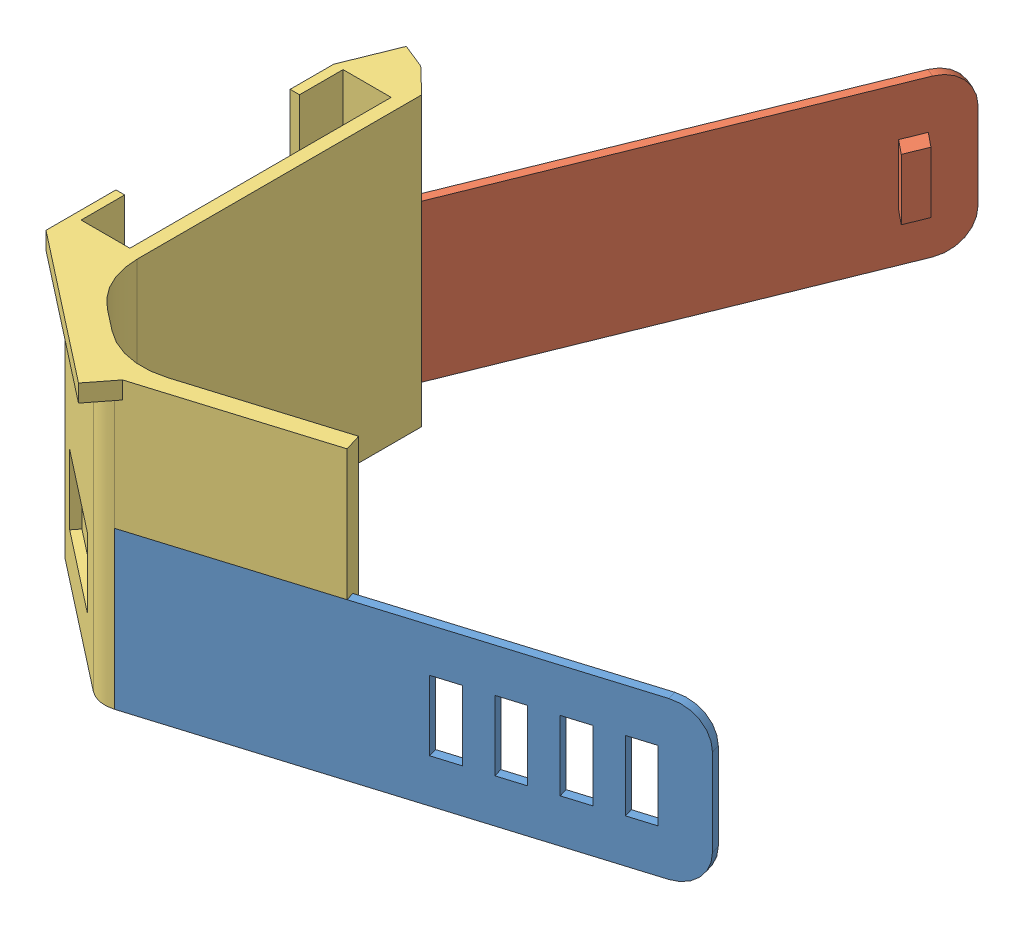
SolidWorks assembly Hybrid Case, configuration Default. Lengths in mm.
Overall size (79.61 33 98.65).
3 component instances, 3 part files, 9 mates.
Components (placement in the parent):
- Back Strap-1: Back Strap [Default] at (62.7568 -15 26.7001) x (0 -1 0) z (-0.956305 0 0.292372) size (18 2 55)
- Front Strap-1: Front Strap [Default] at (13.9565 -33 -51.9223) x (0 1 0) z (-0.374607 0 0.927184) size (18 3 79)
- Solid Back-1: Solid Back [Default] at (-2 -15 30) x (0 0 -1) z (1 0 0) size (52.29 33 39.02)
Mates (geometry in assembly coordinates):
- Coincident1: coincident aligned: plane of Solid Back-1 through (9.5026 0 40.6302) normal (0 1 0)
- Coincident2: coincident aligned: plane of Solid Back-1 through (0 0 30) normal (1 0 0)
- Coincident3: coincident aligned: plane of Solid Back-1 through (-2 0 0) normal (0 0 1)
- Coincident4: coincident anti-aligned: plane of Back Strap-1 through (62.7568 -15 26.7001) normal (-0.292372 0 -0.956305); plane of Solid Back-1 through (2.6128 -33 45.0879) normal (0.292372 0 0.956305)
- Coincident5: coincident anti-aligned: plane of Back Strap-1 through (63.0491 -15 27.6564) normal (0 1 0); plane of Solid Back-1 through (9.5026 -15 40.6302) normal (0 -1 0)
- Coincident6: coincident anti-aligned: plane of Front Strap-1 through (-3.6687 -33 -2.9595) normal (0.374607 0 -0.927184); plane of Solid Back-1 through (-5.523 -10.0004 -3.7087) normal (-0.374607 0 0.927184)
- Coincident7: coincident anti-aligned: plane of Front Strap-1 through (13.9565 -33 -51.9223) normal (0.927184 0 0.374607); plane of Solid Back-1 through (-7.0215 0 0) normal (-0.927184 0 -0.374607)
- Coincident8: coincident anti-aligned: plane of Front Strap-1 through (13.0293 -15 -52.2969) normal (0 1 0); plane of Solid Back-1 through (9.5026 -15 40.6302) normal (0 -1 0)
- Coincident9: coincident anti-aligned: plane of Back Strap-1 through (10.4524 -15 43.7368) normal (-0.956305 0 0.292372); plane of Solid Back-1 through (10.4524 -56.1692 43.7368) normal (0.956305 0 -0.292372)
